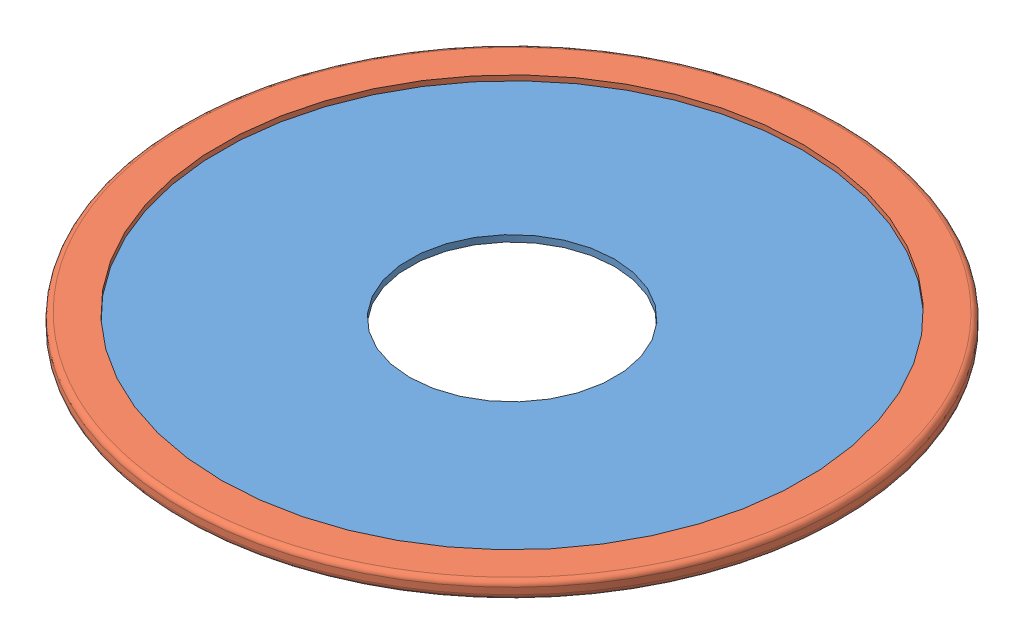
SolidWorks assembly Hatch_Panel_217-6562, configuration Default. Lengths in mm.
Overall size (490.22 12.39 490.22).
2 component instances, 2 part files, 0 mates.
Components (placement in the parent):
- 217-6562-101 Rev3-1: 217-6562-101 Rev3 [Default] at (-50.3588 26.5458 8.5388) size (482.6 4.76 482.6)
- 217-6562-102 Rev1 - Rolled-1: 217-6562-102 Rev1 - Rolled [Default] at (-50.3588 26.5458 8.5388) size (490.22 12.39 490.22)
